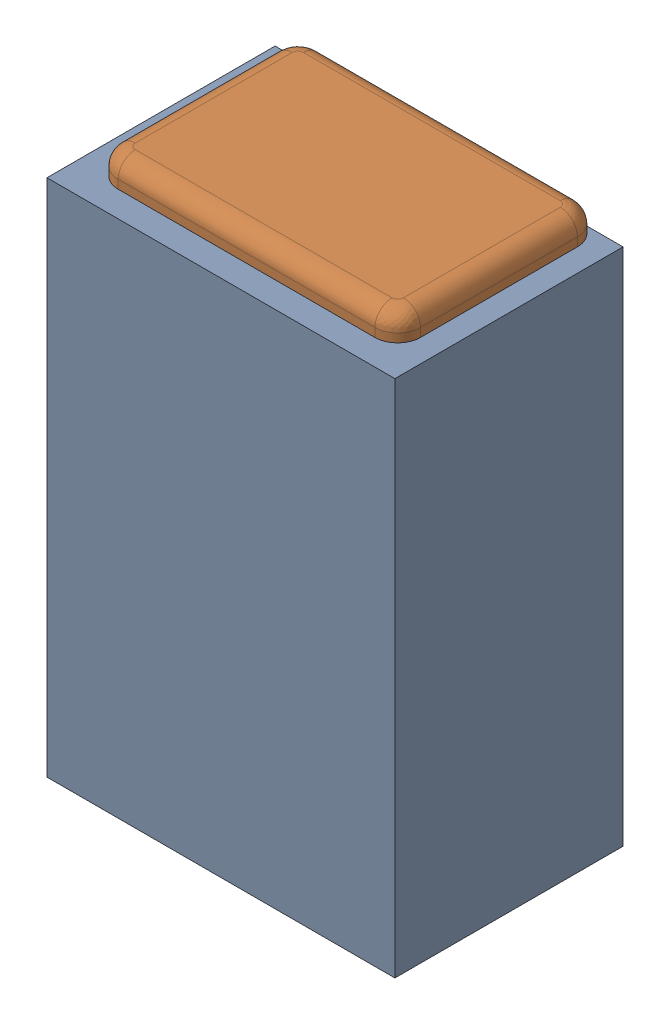
SolidWorks assembly C6, configuration Default. Lengths in mm.
Overall size (0.61 1 0.4).
3 component instances, 2 part files, 0 mates.
Components (placement in the parent):
- 1088881848-1: 1088881848 [Default] at (12.675 38.7 0) size (0.61 0.91 0.4)
  - Extruded-1-1: Extruded-1 [Default] at origin size (0.61 0.91 0.4)
- C0402-1: C0402 [Default] at (12.6749 38.7001 0) x (0 1 0) z (1 0 0) size (1 0.36 0.54)
